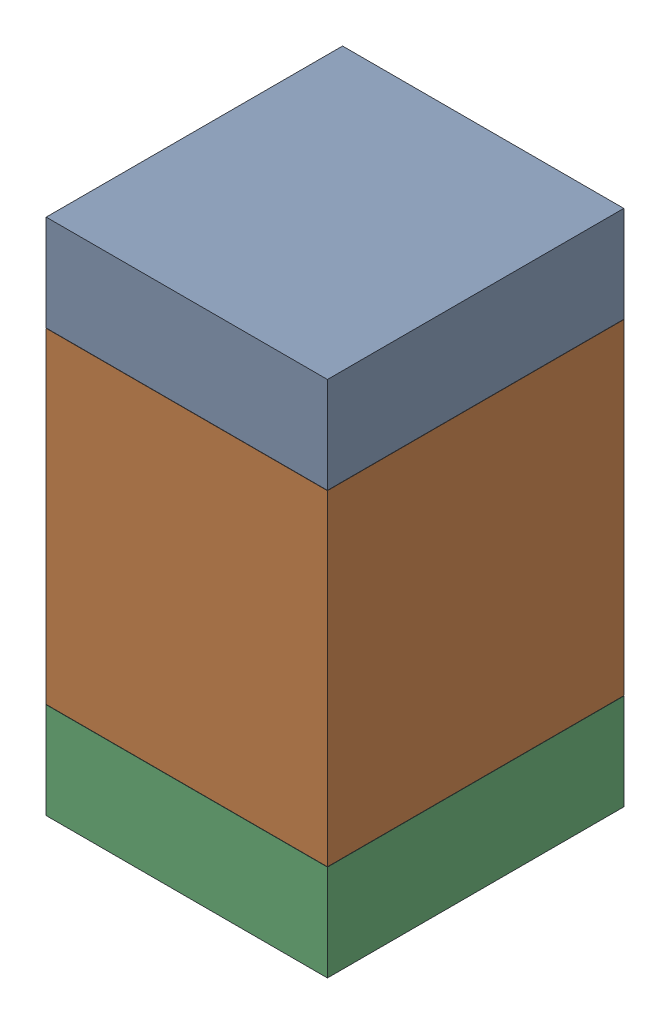
SolidWorks assembly R35, configuration Default. Lengths in mm.
Overall size (0.95 1.75 1).
6 component instances, 2 part files, 0 mates.
Components (placement in the parent):
- 6575495072-1: 6575495072 [Default] at (7.112 2.6175 0) size (0.95 0.32 1)
  - Extruded_6-1: Extruded_6 [Default] at origin size (0.95 0.32 1)
- 6575494912-1: 6575494912 [Default] at (7.112 1.905 0) size (0.95 1.1 1)
  - Extruded_7-1: Extruded_7 [Default] at origin size (0.95 1.1 1)
- 6575495072-2: 6575495072 [Default] at (7.112 1.1925 0) size (0.95 0.32 1)
  - Extruded_6-1: Extruded_6 [Default] at origin size (0.95 0.32 1)
